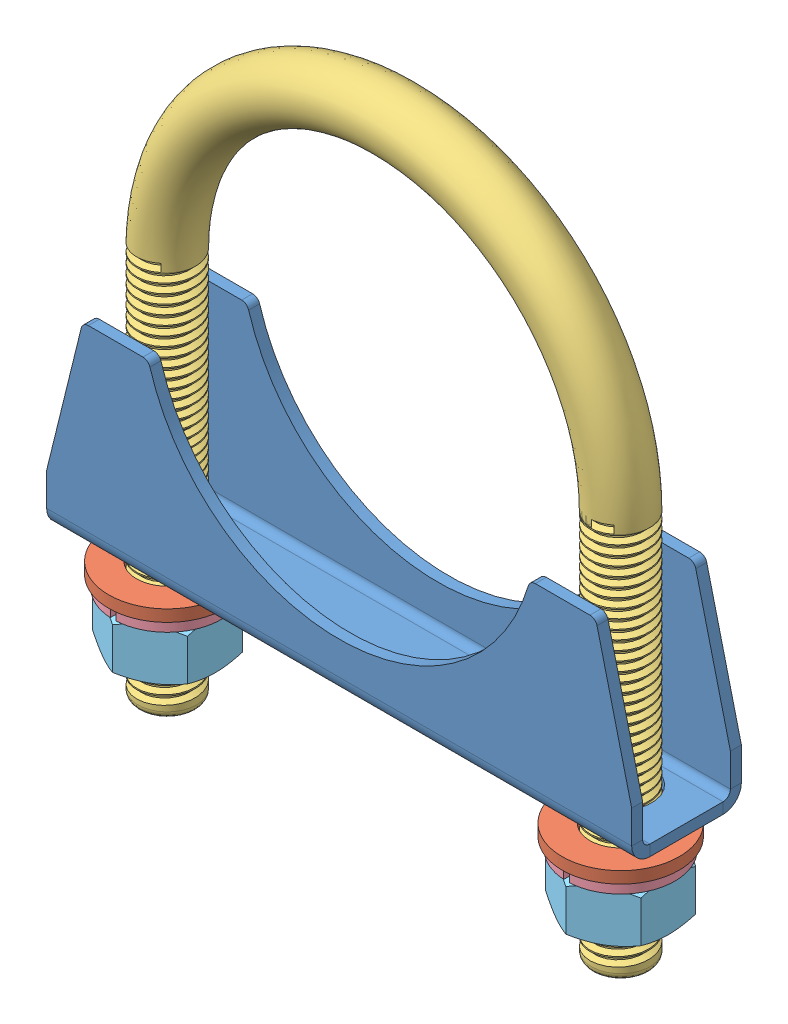
SolidWorks assembly u-bolt-v3, configuration По умолчанию. Lengths in mm.
Overall size (80 88 16).
8 component instances, 5 part files, 24 mates.
Components (placement in the parent):
- Планка хомута 54-4: Планка хомута 54 [По умолчанию] at (-80 1.5 7.5) size (80 27 15)
- plain washer grade a_din-14: plain washer grade a_din [Washer DIN 125 - A 8.4] at (-71 -3 7.5) x (0 1 0) z (0 0 1) size (1.6 16 16)
- Хомут 54-4: Хомут 54 [По умолчанию] at (-40 -19.0353 7.5) x (0 0 -1) z (1 0 0) size (8 88 70)
- plain washer grade a_din-15: plain washer grade a_din [Washer DIN 125 - A 8.4] at (-9 -3 7.5) x (0 1 0) z (0 0 1) size (1.6 16 16)
- curved spring lock washer_din-14: curved spring lock washer_din [Spring washer DIN 128 - A8] at (-9 -4.6 7.5) x (0 1 0) z (0 0 1) size (1.6 14.8 14.79)
- curved spring lock washer_din-15: curved spring lock washer_din [Spring washer DIN 128 - A8] at (-71 -4.6 7.5) x (0 1 0) z (0 0 1) size (1.6 14.8 14.79)
- hex nut style 1 gradeab_iso-2: hex nut style 1 gradeab_iso [ISO - 4032 - M8 - D - N] at (-71 -13 7.5) x (1 0 0) z (0 -1 0) size (13 15.01 6.8)
- hex nut style 1 gradeab_iso-5: hex nut style 1 gradeab_iso [ISO - 4032 - M8 - D - N] at (-9 -13 7.5) x (1 0 0) z (0 -1 0) size (13 15.01 6.8)
Mates (geometry in assembly coordinates):
- Ширина15: width: plane of ? through (-111.2404 29.0179 -46) normal (0 0 1); plane of ? through (-111.2404 29.0179 46) normal (0 0 -1); plane of ? through (-2.2945 -2.6419 45) normal (0 0 1); plane of ? through (-2.2945 -2.6419 -45) normal (0 0 -1)
- Концентричный65: concentric: cylinder of ? through (-58.998 6.8428 45.3) axis (0 0 1) radius 2.5; cylinder of ? through (-58.998 6.8428 48.5) axis (0 0 -1) radius 3.25
- Концентричный66: concentric: cylinder of ? through (-147.5333 44.0785 31) axis (0.60572 0.795678 0) radius 5.5; cylinder of ? through (-118.1926 82.6207 31) axis (-0.60572 -0.795678 0) radius 5
- Концентричный67: concentric: cylinder of ? through (-147.5333 44.0785 -31) axis (0.60572 0.795678 0) radius 5.5; cylinder of ? through (-152.1129 38.0627 -31) axis (0.60572 0.795678 0) radius 5
- Концентричный68: concentric: cylinder of ? through (-187.3172 74.3645 31) axis (0.60572 0.795678 0) radius 5.5; cylinder of ? through (-160.7235 109.2981 31) axis (-0.60572 -0.795678 0) radius 5
- Концентричный69: concentric: cylinder of ? through (-187.3172 74.3645 -31) axis (0.60572 0.795678 0) radius 5.5; cylinder of ? through (-194.6438 64.7402 -31) axis (0.60572 0.795678 0) radius 5
- Совпадение64: coincident: plane of ? through (-39.75 -26.8639 31) normal (0 -1 0); plane of ? through (-89.75 -26.8639 31) normal (0 -1 0)
- Концентричный84: concentric anti-aligned: circle of Планка хомута 54-4; cylinder of Хомут 54-4 through (-9 -19.0353 7.5) axis (0 1 0) radius 4
- Концентричный85: concentric aligned: cylinder of Планка хомута 54-4 through (-71 16.0551 7.5) axis (0 -1 0) radius 4.25; cylinder of Хомут 54-4 through (-71 33.9647 7.5) axis (0 -1 0) radius 4
- Концентричный91: concentric aligned: cylinder of plain washer grade a_din-15 through (-9 -37.925 7.5) axis (0 -1 0) radius 8; cylinder of curved spring lock washer_din-14 through (-9 -39.525 7.5) axis (0 -1 0) radius 7.4
- Совпадение83: coincident anti-aligned: plane of plain washer grade a_din-15 through (-17 -4.6 7.5) normal (0 -1 0); plane of curved spring lock washer_din-14 through (-13.55 -4.6 7.5) normal (0 1 0)
- Концентричный92: concentric aligned: cylinder of plain washer grade a_din-14 through (-71 -37.925 7.5) axis (0 -1 0) radius 8; cylinder of curved spring lock washer_din-15 through (-71 -39.525 7.5) axis (0 -1 0) radius 7.4
- Совпадение84: coincident anti-aligned: plane of plain washer grade a_din-14 through (-79 -4.6 7.5) normal (0 -1 0); plane of curved spring lock washer_din-15 through (-75.55 -4.6 7.5) normal (0 1 0)
- Концентричный94: concentric aligned: cylinder of curved spring lock washer_din-15 through (-71 -39.525 7.5) axis (0 -1 0) radius 7.4; cylinder of hex nut style 1 gradeab_iso-2 through (-71 12.0375 7.5) axis (0 -1 0) radius 4
- Совпадение86: coincident anti-aligned: plane of curved spring lock washer_din-15 through (-78.4 -6.2 7.5) normal (0 -1 0); plane of hex nut style 1 gradeab_iso-2 through (-71 -6.2 15.0056) normal (0 1 0)
- Концентричный97: concentric aligned: cylinder of curved spring lock washer_din-14 through (-9 -39.525 7.5) axis (0 -1 0) radius 7.4; cylinder of hex nut style 1 gradeab_iso-5 through (-9 12.0375 7.5) axis (0 -1 0) radius 4
- Совпадение89: coincident anti-aligned: plane of curved spring lock washer_din-14 through (-16.4 -6.2 7.5) normal (0 -1 0); plane of hex nut style 1 gradeab_iso-5 through (-9 -6.2 15.0056) normal (0 1 0)
- Совпадение90: coincident anti-aligned: plane of Планка хомута 54-4 through (0 2.5 0) normal (0 0 -1)
- Совпадение91: coincident aligned: plane of Планка хомута 54-4 through (0 2.5 15) normal (1 0 0)
- Совпадение92: coincident anti-aligned: plane of Планка хомута 54-4 through (0 0 12.5) normal (0 -1 0)
- Концентричный98: concentric aligned: cylinder of Планка хомута 54-4 through (-71 16.0551 7.5) axis (0 -1 0) radius 4.25; cylinder of plain washer grade a_din-14 through (-71 -37.925 7.5) axis (0 -1 0) radius 4.2
- Расстояние1: distance = 3 mm anti-aligned: plane of plain washer grade a_din-14 through (-75.2 -3 7.5) normal (0 1 0); plane of Планка хомута 54-4 through (0 0 12.5) normal (0 -1 0)
- Концентричный99: concentric aligned: cylinder of Планка хомута 54-4 through (-9 16.0551 7.5) axis (0 -1 0) radius 4.25; cylinder of plain washer grade a_din-15 through (-9 -37.925 7.5) axis (0 -1 0) radius 4.2
- Совпадение94: coincident aligned: plane of hex nut style 1 gradeab_iso-2 through (-71 -13 15.0056) normal (0 -1 0); plane of hex nut style 1 gradeab_iso-5 through (-9 -13 15.0056) normal (0 -1 0)
